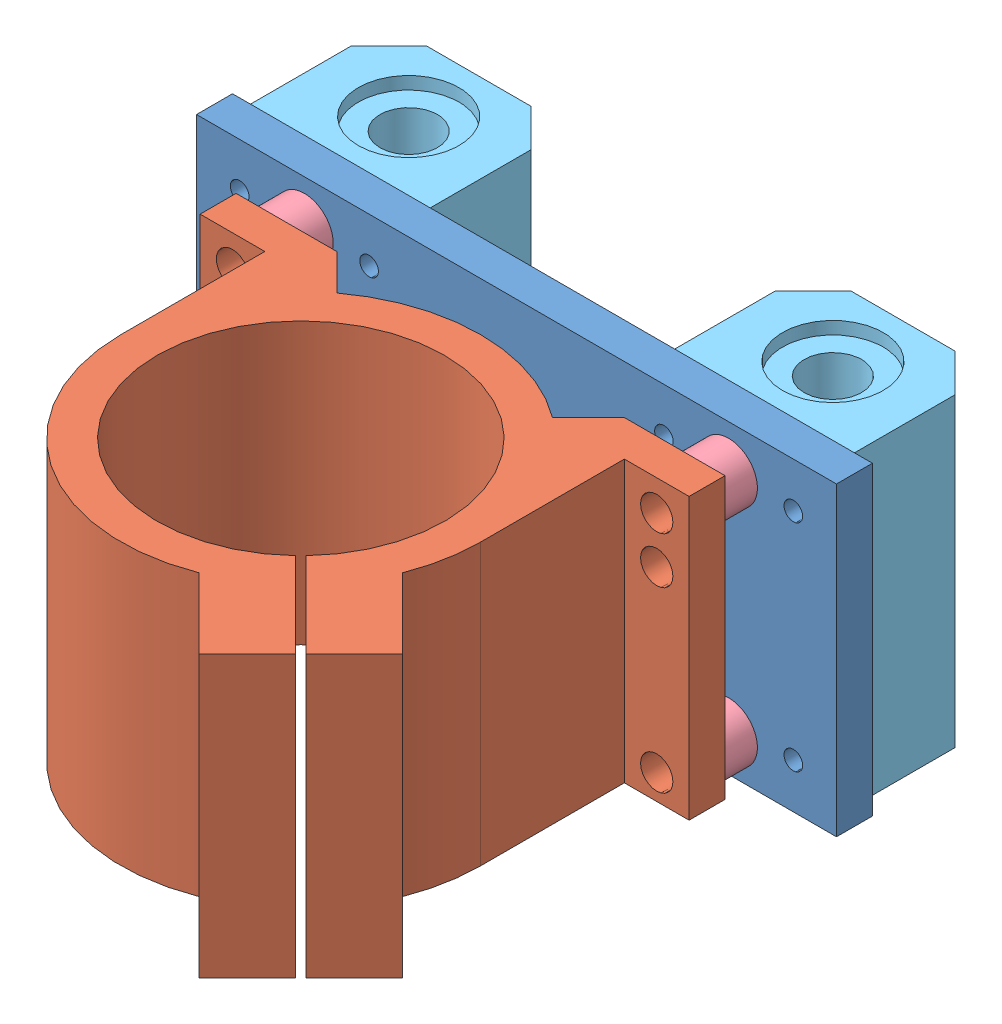
SolidWorks assembly new spindle frame, configuration Default. Lengths in mm.
Overall size (178 85 174.65).
9 component instances, 5 part files, 12 mates.
Components (placement in the parent):
- Z back panel-1: Z back panel [Default] at (-38.9534 148.5728 161.2451) size (178 85 10)
- spindle hoop-1: spindle hoop [Default] at (-38.9534 109.5728 231.2451) x (-1 0 0) z (0 0 -1) size (136 78 116.15)
- screw block-1: screw block [Default] at (-38.9534 160.0728 146.2451) x (1 0 0) z (0 -1 0) size (50 30 47.5)
- washer m8-1: washer m8 [Default] at (-97.9534 179.0728 171.2451) size (16 16 10)
- washer m8-2: washer m8 [Default] at (-97.9534 118.0728 171.2451) size (16 16 10)
- washer m8-3: washer m8 [Default] at (20.0466 179.0728 171.2451) size (16 16 10)
- washer m8-4: washer m8 [Default] at (20.0466 116.5728 171.2451) size (16 16 10)
- long sliding block-1: long sliding block [Default] at (-97.9534 148.5728 122.7451) size (50 85 38.5)
- long sliding block-2: long sliding block [Default] at (20.0466 148.5728 122.7451) size (50 85 38.5)
Mates (geometry in assembly coordinates):
- ProfileCenter6: profile center = 0 mm aligned: circle of screw block-1; circle of Z back panel-1
- Concentric6: concentric anti-aligned: cylinder of Z back panel-1 through (-21.4534 130.0728 171.2451) axis (0 0 -1) radius 2.6; cylinder of screw block-1 through (-21.4534 130.0728 161.2451) axis (0 0 1) radius 2.1
- ProfileCenter7: profile center = 0 mm aligned: circle of washer m8-1; circle of Z back panel-1
- ProfileCenter8: profile center = 0 mm aligned: circle of washer m8-2; circle of Z back panel-1
- ProfileCenter9: profile center = 0 mm aligned: circle of washer m8-3; circle of Z back panel-1
- ProfileCenter10: profile center = 0 mm aligned: circle of washer m8-4; circle of Z back panel-1
- ProfileCenter11: profile center = 0 mm anti-aligned: circle of washer m8-3; circle of spindle hoop-1
- Concentric7: concentric aligned: cylinder of spindle hoop-1 through (-97.9534 118.0728 181.2451) axis (0 0 -1) radius 4.5; cylinder of washer m8-2 through (-97.9534 118.0728 181.2451) axis (0 0 -1) radius 4.1
- ProfileCenter12: profile center = 0 mm aligned: circle of Z back panel-1; circle of long sliding block-2
- Concentric9: concentric anti-aligned: cylinder of Z back panel-1 through (2.0466 118.5728 171.2451) axis (0 0 -1) radius 2.6; cylinder of long sliding block-2 through (2.0466 118.5728 161.2451) axis (0 0 1) radius 2.1
- Concentric10: concentric anti-aligned: cylinder of Z back panel-1 through (-79.9534 118.5728 171.2451) axis (0 0 -1) radius 2.6; cylinder of long sliding block-1 through (-79.9534 118.5728 161.2451) axis (0 0 1) radius 2.1
- ProfileCenter13: profile center = 0 mm aligned: circle of long sliding block-1; circle of Z back panel-1
